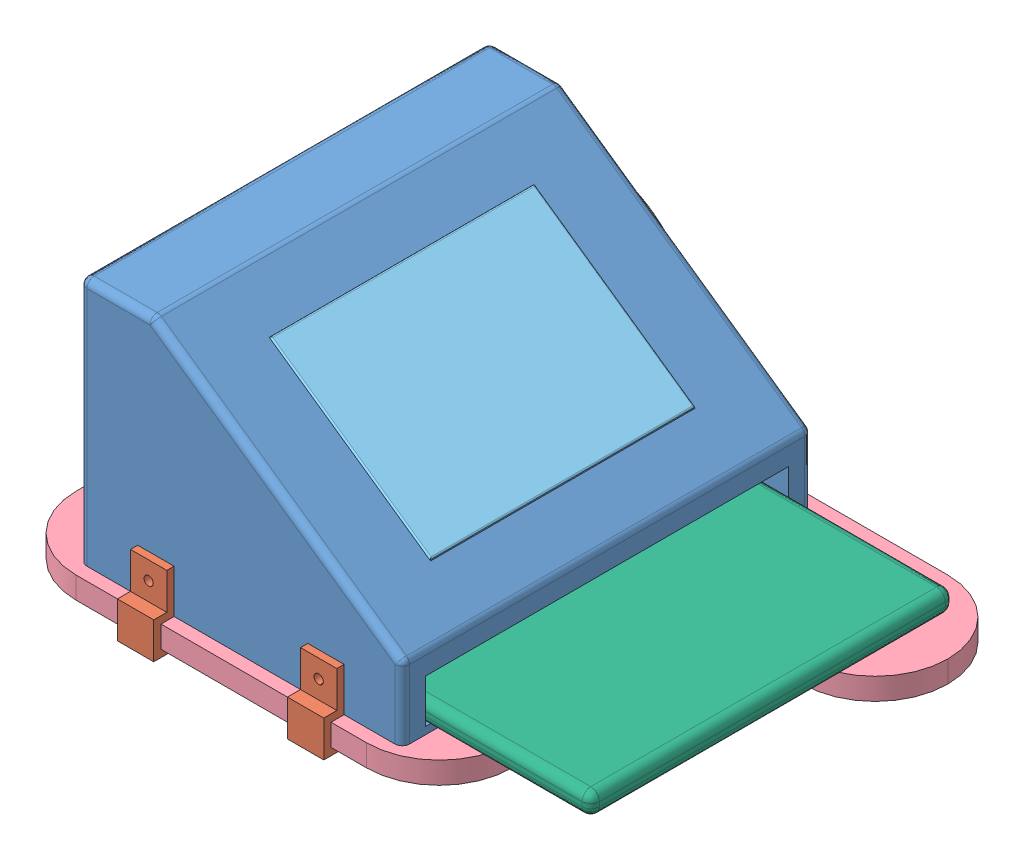
SolidWorks assembly Assem2, configuration Default. Lengths in mm.
Overall size (400 190.45 310).
7 component instances, 6 part files, 14 mates.
Components (placement in the parent):
- BaseNoTouch-1: BaseNoTouch [Default] at (194.3293 174.9825 150.5599) size (222.02 170.45 282)
- Agarre-1: Agarre [Default] at (129.3293 139.9825 291.5599) x (0 0 -1) z (1 0 0) size (310 50 25)
- Agarre-2: Agarre [Default] at (12.3074 139.9825 291.5599) x (0 0 -1) z (1 0 0) size (310 50 25)
- Mouse-1: Mouse [Default] at (-5.976 229.7836 170.5599) x (0.819152 -0.573576 0) z (0 0 1) size (120 55 30)
- Paleta-1: Paleta [Default] at (228.8697 124.9825 141.5599) x (0 0 1) z (1 0 0) size (300 15 400)
- Tablet-1: Tablet [Default] at (103.5119 228.8073 291.5599) x (0 0 -1) z (0.819152 -0.573576 0) size (182 9 135)
- Teclado-1: Teclado [Default] at (233.0527 144.9825 291.5599) x (0 0 -1) z (-1 0 0) size (250 15 150)
Mates (geometry in assembly coordinates):
- Coincident1: coincident anti-aligned: plane of BaseNoTouch-1 through (194.3293 174.9825 432.5599) normal (0 0 1); plane of Agarre-1 through (154.3293 139.9825 432.5599) normal (0 0 -1)
- Concentric2: concentric aligned: circle of BaseNoTouch-1; circle of Agarre-1
- Coincident4: coincident anti-aligned: plane of BaseNoTouch-1 through (194.3293 174.9825 432.5599) normal (0 0 1); plane of Agarre-2 through (37.3074 139.9825 432.5599) normal (0 0 -1)
- Concentric3: concentric aligned: circle of BaseNoTouch-1; circle of Agarre-2
- Coincident6: coincident anti-aligned: plane of BaseNoTouch-1 through (44.3293 129.9825 150.5599) normal (0 1 0); plane of Teclado-1 through (233.0527 129.9825 291.5599) normal (0 -1 0)
- Coincident7: coincident anti-aligned: plane of BaseNoTouch-1 through (44.3293 174.9825 416.5599) normal (0 0 -1); plane of Teclado-1 through (158.0527 129.9825 416.5599) normal (0 0 1)
- Coincident8: coincident anti-aligned: plane of BaseNoTouch-1 through (189.7407 168.4293 150.5599) normal (0.573576 0.819152 0); plane of Tablet-1 through (103.5119 228.8073 291.5599) normal (-0.573576 -0.819152 0)
- Coincident9: coincident aligned: line of BaseNoTouch-1 through (52.8077 274.077 200.5599) axis (0.819152 -0.573576 0); line of Tablet-1 through (52.8077 274.077 200.5599) axis (0.819152 -0.573576 0)
- Coincident10: coincident anti-aligned: line of BaseNoTouch-1 through (52.8077 274.077 200.5599) axis (0 0 1); line of Tablet-1 through (52.8077 274.077 382.5599) axis (0 0 -1)
- Coincident11: coincident anti-aligned: plane of BaseNoTouch-1 through (194.3293 174.9825 170.5599) normal (0 0 -1); plane of Mouse-1 through (25.5707 274.837 170.5599) normal (0 0 1)
- Coincident12: coincident anti-aligned: line of BaseNoTouch-1 through (115.6774 211.7435 165.5599) axis (-0.819152 0.573576 0); line of Mouse-1 through (33.7622 269.1012 165.5599) axis (0.819152 -0.573576 0)
- Coincident13: coincident anti-aligned: line of BaseNoTouch-1 through (19.8349 266.6454 165.5599) axis (-0.573576 -0.819152 0); line of Mouse-1 through (-0.2403 237.9751 165.5599) axis (0.573576 0.819152 0)
- Coincident14: coincident anti-aligned: plane of BaseNoTouch-1 through (194.3293 124.9825 432.5599) normal (0 -1 0); plane of Paleta-1 through (228.8697 124.9825 141.5599) normal (0 1 0)
- Coincident15: coincident anti-aligned: plane of Agarre-1 through (154.3293 139.9825 141.5599) normal (0 0 1); plane of Paleta-1 through (228.8697 109.9825 141.5599) normal (0 0 -1)
